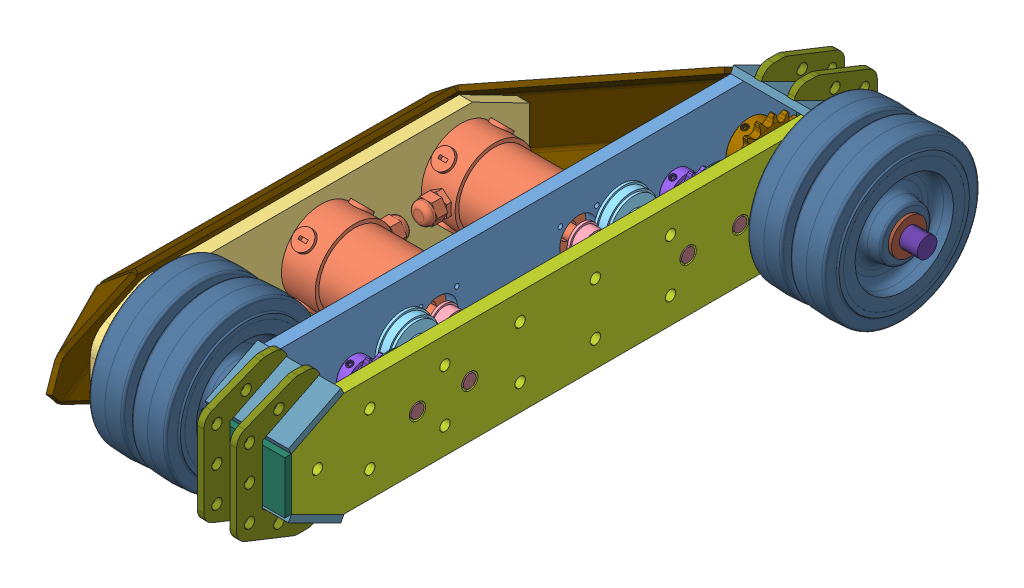
SolidWorks assembly PhobusWheelPod, configuration Default. Lengths in mm.
Overall size (564.9 195.73 652.93).
50 component instances, 18 part files, 92 mates.
Components (placement in the parent):
- WheelPodMotorFaceRail-1: WheelPodMotorFaceRail [Default] at (-65.4677 24.4329 -61.6038) size (12.7 101.6 558.8)
- s28-150magmotor-1: s28-150magmotor [Default] at (-65.4677 24.4329 -61.6038) x (1 0 0) z (0 0.707107 0.707107) size (163.83 88.45 88.45)
- WheelPodOuterRail-1: WheelPodOuterRail [Default] at (-179.7677 24.4329 -61.6038) size (12.7 101.6 414.02)
- Gear16T16P_6325K13-1: Gear16T16P_6325K13 [Default] at (-49.5927 24.4329 -61.6038) x (1 0 0) z (0 -0.155736 0.987799) size (23.81 28.7 28.7)
- Gear32T16P_6325K21 MOD-1: Gear32T16P_6325K21 MOD [Default] at (-49.5927 24.4329 -23.5038) size (25.4 54.1 54.1)
- Gear48T16P_6325K21-2: Gear48T16P_6325K21 [Default] at (-0.3802 24.4329 27.2962) x (-1 0 0) z (0 -0.862539 -0.505991) size (25.4 79.5 79.5)
- Gear16T16P_6325K13-2: Gear16T16P_6325K13 [Default] at (-0.3802 24.4329 -23.5038) x (-1 0 0) z (0 0 -1) size (23.81 28.7 28.7)
- WheelPodChassisRail-1: WheelPodChassisRail [Default] at (2.7948 24.4329 -61.6038) size (12.7 101.6 558.8)
- 2500T42 10t Num40 0500Bore-1: 2500T42 10t Num40 0500Bore [2500T421] at (-29.387 24.4329 27.2962) x (0 0.894943 0.446181) z (-1 0 0) size (44.9 46.71 22.23)
- 2500T473 15t Num40 0750Bore-1: 2500T473 15t Num40 0750Bore [2500T473] at (-29.387 24.4329 99.0512) x (0 0.924225 0.381849) z (-1 0 0) size (67.07 66.71 22.23)
- 6inColsonWithHub-1: 6inColsonWithHub [Default] at (-122.9 18.8142 107.5418) x (1 0 0) z (0 0.938189 0.346124) size (44.45 152.4 152.4)
  - Colson-6in x 1_5in-1: Colson-6in x 1_5in [Default] at (-17.1802 9.9106 2.3327) size (41.28 152.4 152.4)
    - Colson-4.06108.449_Wheel series 4_6Hi-tech-performa-flat-tread-1: Colson-4.06108.449_Wheel series 4_6Hi-tech-performa-flat-tread [Default] at origin size (41.28 152.4 152.4)
  - 1-625in Wide ColsonHubCappedFlanged-1: 1-625in Wide ColsonHubCappedFlanged [Default] at (-37.8177 9.9106 2.3327) size (44.45 34.29 34.29)
- 6inColsonWithHub-2: 6inColsonWithHub [Default] at (-115.9854 23.7371 109.2088) x (-1 0 0) z (0 -0.955464 -0.295107) size (44.45 152.4 152.4)
  - Colson-6in x 1_5in-1: Colson-6in x 1_5in [Default] at (-17.1802 9.9106 2.3327) size (41.28 152.4 152.4)
    - Colson-4.06108.449_Wheel series 4_6Hi-tech-performa-flat-tread-1: Colson-4.06108.449_Wheel series 4_6Hi-tech-performa-flat-tread [Default] at origin size (41.28 152.4 152.4)
  - 1-625in Wide ColsonHubCappedFlanged-1: 1-625in Wide ColsonHubCappedFlanged [Default] at (-37.8177 9.9106 2.3327) size (44.45 34.29 34.29)
- WheelPod 0750 shaft-1: WheelPod 0750 shaft [Default] at (-179.7677 24.4329 99.0512) size (171.45 19.05 19.05)
- WheelPod 0500 shaft-1: WheelPod 0500 shaft [Default] at (-65.4677 24.4329 27.2962) size (80.96 12.7 12.7)
- WheelPod 0500 shaft-2: WheelPod 0500 shaft [Default] at (-65.4677 24.4329 -23.5038) size (80.96 12.7 12.7)
- DrivePodFrontAnglePlate-1: DrivePodFrontAnglePlate [Default] at (-24.9865 62.6121 124.293) x (1 0 0) z (0 -0.447214 0.894427) size (80.96 6.35 57.15)
- DrivePodFrontAnglePlate-2: DrivePodFrontAnglePlate [Default] at (-24.9865 -19.4258 127.1328) x (1 0 0) z (0 0.447214 0.894427) size (80.96 6.35 57.15)
- DrivePodFrontPlate-1: DrivePodFrontPlate [Default] at (-24.9865 24.4329 149.8512) x (1 0 0) z (0 -1 0) size (80.96 6.35 50.8)
- PodAttachmentBracket-1: PodAttachmentBracket [Default] at (-50.3865 24.4329 -61.6038) size (6.35 133.35 81.05)
- PodAttachmentBracket-2: PodAttachmentBracket [Default] at (-18.6365 24.4329 -61.6038) size (6.35 133.35 81.05)
- s28-150magmotor-2: s28-150magmotor [Default] at (-65.4677 24.4329 -197.4938) x (1 0 0) z (0 -0.707107 -0.707107) size (163.83 88.45 88.45)
- Gear16T16P_6325K13-3: Gear16T16P_6325K13 [Default] at (-49.5927 24.4329 -197.4938) x (1 0 0) z (0 -0.155736 0.987799) size (23.81 28.7 28.7)
- Gear32T16P_6325K21 MOD-2: Gear32T16P_6325K21 MOD [Default] at (-49.5927 24.4329 -235.5938) size (25.4 54.1 54.1)
- Gear48T16P_6325K21-3: Gear48T16P_6325K21 [Default] at (-0.3802 24.4329 -286.3938) x (-1 0 0) z (0 -0.862539 -0.505991) size (25.4 79.5 79.5)
- Gear16T16P_6325K13-4: Gear16T16P_6325K13 [Default] at (-0.3802 24.4329 -235.5938) x (-1 0 0) z (0 0 -1) size (23.81 28.7 28.7)
- 2500T42 10t Num40 0500Bore-2: 2500T42 10t Num40 0500Bore [2500T421] at (-29.387 24.4329 -286.3938) x (0 0.894943 0.446181) z (-1 0 0) size (44.9 46.71 22.23)
- 2500T473 15t Num40 0750Bore-2: 2500T473 15t Num40 0750Bore [2500T473] at (-29.387 24.4329 -358.1488) x (0 0.924225 0.381849) z (-1 0 0) size (67.07 66.71 22.23)
- 6inColsonWithHub-3: 6inColsonWithHub [Default] at (59.6625 18.8142 -349.6582) x (1 0 0) z (0 0.938189 0.346124) size (44.45 152.4 152.4)
  - Colson-6in x 1_5in-1: Colson-6in x 1_5in [Default] at (-17.1802 9.9106 2.3327) size (41.28 152.4 152.4)
    - Colson-4.06108.449_Wheel series 4_6Hi-tech-performa-flat-tread-1: Colson-4.06108.449_Wheel series 4_6Hi-tech-performa-flat-tread [Default] at origin size (41.28 152.4 152.4)
  - 1-625in Wide ColsonHubCappedFlanged-1: 1-625in Wide ColsonHubCappedFlanged [Default] at (-37.8177 9.9106 2.3327) size (44.45 34.29 34.29)
- WheelPod 0500 shaft-3: WheelPod 0500 shaft [Default] at (-65.4677 24.4329 -286.3938) size (80.96 12.7 12.7)
- WheelPod 0500 shaft-4: WheelPod 0500 shaft [Default] at (-65.4677 24.4329 -235.5938) size (80.96 12.7 12.7)
- WheelPod 0750 shaft Rear-1: WheelPod 0750 shaft Rear [Default] at (-65.4677 24.4329 -358.1488) size (190.5 19.05 19.05)
- 6inColsonWithHub-4: 6inColsonWithHub [Default] at (66.5771 14.4402 -356.1979) x (-1 0 0) z (0 0.038351 -0.999264) size (44.45 152.4 152.4)
  - Colson-6in x 1_5in-1: Colson-6in x 1_5in [Default] at (-17.1802 9.9106 2.3327) size (41.28 152.4 152.4)
    - Colson-4.06108.449_Wheel series 4_6Hi-tech-performa-flat-tread-1: Colson-4.06108.449_Wheel series 4_6Hi-tech-performa-flat-tread [Default] at origin size (41.28 152.4 152.4)
  - 1-625in Wide ColsonHubCappedFlanged-1: 1-625in Wide ColsonHubCappedFlanged [Default] at (-37.8177 9.9106 2.3327) size (44.45 34.29 34.29)
- DrivePodFrontPlate-2: DrivePodFrontPlate [Default] at (-24.9865 24.4329 -415.2988) x (1 0 0) z (0 -1 0) size (80.96 6.35 50.8)
- DrivePodFrontAnglePlate-3: DrivePodFrontAnglePlate [Default] at (-24.9865 -19.4258 -386.2303) x (1 0 0) z (0 -0.447214 0.894427) size (80.96 6.35 57.15)
- PodAttachmentBracket-3: PodAttachmentBracket [Default] at (-31.3365 24.4329 -197.4938) x (-1 0 0) z (0 0 -1) size (6.35 133.35 81.05)
- DrivePodFrontAnglePlate-4: DrivePodFrontAnglePlate [Default] at (-24.9865 62.6121 -383.3905) x (1 0 0) z (0 0.447214 0.894427) size (80.96 6.35 57.15)
- PodAttachmentBracket-4: PodAttachmentBracket [Default] at (0.4135 24.4329 -197.4938) x (-1 0 0) z (0 0 -1) size (6.35 133.35 81.05)
- DrivePodSideArmorPanelA-1: DrivePodSideArmorPanelA [Default] at (-140.0311 24.4329 -322.1877) x (-0.619644 0 0.784883) z (0 1 0) size (543.24 290.85 112.3)
Mates (geometry in assembly coordinates):
- Concentric1: concentric aligned: cylinder of s28-150magmotor-1 through (-21.5257 24.4329 -61.6038) axis (-1 0 0) radius 6.35; cylinder of WheelPodMotorFaceRail-1 through (-52.7677 24.4329 -61.6038) axis (-1 0 0) radius 18.415
- Coincident1: coincident anti-aligned: plane of WheelPodMotorFaceRail-1 through (-65.4677 24.4329 -61.6038) normal (-1 0 0); plane of s28-150magmotor-1 through (-65.4677 24.4329 -61.6038) normal (1 0 0)
- Parallel1: parallel aligned: plane of WheelPodMotorFaceRail-1 through (-52.7677 75.2329 -61.6038) normal (0 1 0); plane of s28-150magmotor-1 through (-154.0752 34.4329 -114.6038) normal (0 1 0)
- Coincident2: coincident anti-aligned: plane of s28-150magmotor-1 through (-167.0677 24.4329 -61.6038) normal (-1 0 0); plane of WheelPodOuterRail-1 through (-167.0677 24.4329 -61.6038) normal (1 0 0)
- Concentric2: concentric anti-aligned: cylinder of s28-150magmotor-1 through (-185.3557 24.4329 -61.6038) axis (1 0 0) radius 6.35; cylinder of WheelPodOuterRail-1 through (-167.0677 24.4329 -61.6038) axis (-1 0 0) radius 7.9375
- Coincident3: coincident aligned: plane of WheelPodMotorFaceRail-1 through (-52.7677 75.2329 -61.6038) normal (0 1 0); plane of WheelPodOuterRail-1 through (-167.0677 75.2329 -61.6038) normal (0 1 0)
- Distance1: distance = 3.175 mm anti-aligned: plane of Gear32T16P_6325K21 MOD-1 through (-49.5927 24.4329 -23.5038) normal (-1 0 0); plane of WheelPodMotorFaceRail-1 through (-52.7677 24.4329 -61.6038) normal (1 0 0)
- Concentric3: concentric aligned: cylinder of WheelPodMotorFaceRail-1 through (-52.7677 24.4329 -23.5038) axis (-1 0 0) radius 7.9375; cylinder of Gear32T16P_6325K21 MOD-1 through (-24.1927 24.4329 -23.5038) axis (-1 0 0) radius 6.35
- Coincident5: coincident aligned: plane of Gear32T16P_6325K21 MOD-1 through (-36.8927 24.4329 -23.5038) normal (1 0 0); plane of Gear16T16P_6325K13-1 through (-36.8927 24.4329 -61.6038) normal (1 0 0)
- Concentric4: concentric aligned: cylinder of s28-150magmotor-1 through (-21.5257 24.4329 -61.6038) axis (-1 0 0) radius 6.35; cylinder of Gear16T16P_6325K13-1 through (-25.7802 24.4329 -61.6038) axis (-1 0 0) radius 6.35
- Coincident9: coincident aligned: plane of WheelPodMotorFaceRail-1 through (-52.7677 75.2329 -61.6038) normal (0 1 0); plane of WheelPodChassisRail-1 through (15.4948 75.2329 -61.6038) normal (0 1 0)
- Concentric10: concentric aligned: cylinder of WheelPodOuterRail-1 through (-167.0677 24.4329 99.0512) axis (-1 0 0) radius 11.1125; cylinder of 6inColsonWithHub-1/1-625in Wide ColsonHubCappedFlanged-1 through (-119.4427 24.4329 99.0512) axis (-1 0 0) radius 6.35
- Concentric12: concentric anti-aligned: cylinder of WheelPodOuterRail-1 through (-167.0677 24.4329 99.0512) axis (-1 0 0) radius 11.1125; cylinder of 6inColsonWithHub-2/1-625in Wide ColsonHubCappedFlanged-1 through (-119.4427 24.4329 99.0512) axis (1 0 0) radius 6.35
- Concentric13: concentric aligned: cylinder of WheelPodMotorFaceRail-1 through (-52.7677 24.4329 99.0512) axis (-1 0 0) radius 11.1125; cylinder of WheelPodOuterRail-1 through (-167.0677 24.4329 99.0512) axis (-1 0 0) radius 11.1125
- Coincident13: coincident anti-aligned: plane of 6inColsonWithHub-1/1-625in Wide ColsonHubCappedFlanged-1 through (-119.4427 24.4329 99.0512) normal (1 0 0); plane of 6inColsonWithHub-2/1-625in Wide ColsonHubCappedFlanged-1 through (-119.4427 24.4329 99.0512) normal (-1 0 0)
- Distance4: distance = 3.175 mm anti-aligned: plane of 6inColsonWithHub-1/1-625in Wide ColsonHubCappedFlanged-1 through (-163.8927 24.4329 99.0512) normal (-1 0 0); plane of WheelPodOuterRail-1 through (-167.0677 24.4329 -61.6038) normal (1 0 0)
- Concentric14: concentric anti-aligned: cylinder of Gear32T16P_6325K21 MOD-1 through (-24.1927 24.4329 -23.5038) axis (-1 0 0) radius 6.35; cylinder of Gear16T16P_6325K13-2 through (-24.1927 24.4329 -23.5038) axis (1 0 0) radius 6.35
- Coincident14: coincident aligned: plane of Gear32T16P_6325K21 MOD-1 through (-24.1927 24.4329 -25.0913) normal (0 0 1); plane of Gear16T16P_6325K13-2 through (-24.1927 24.4329 -25.0913) normal (0 0 1)
- Coincident15: coincident anti-aligned: plane of Gear32T16P_6325K21 MOD-1 through (-24.1927 24.4329 -23.5038) normal (1 0 0); plane of Gear16T16P_6325K13-2 through (-24.1927 24.4329 -23.5038) normal (-1 0 0)
- Coincident16: coincident aligned: plane of Gear48T16P_6325K21-2 through (-0.3802 24.4329 27.2962) normal (1 0 0); plane of Gear16T16P_6325K13-2 through (-0.3802 24.4329 -23.5038) normal (1 0 0)
- Concentric15: concentric aligned: cylinder of Gear48T16P_6325K21-2 through (-25.7802 24.4329 27.2962) axis (1 0 0) radius 6.35; cylinder of 2500T42 10t Num40 0500Bore-1 through (-48.0052 24.4329 27.2962) axis (1 0 0) radius 6.35
- Concentric16: concentric anti-aligned: cylinder of WheelPodMotorFaceRail-1 through (-52.7677 24.4329 27.2962) axis (-1 0 0) radius 7.9375; cylinder of Gear48T16P_6325K21-2 through (-25.7802 24.4329 27.2962) axis (1 0 0) radius 6.35
- Coincident17: coincident anti-aligned: plane of Gear48T16P_6325K21-2 through (-25.7802 24.4329 27.2962) normal (-1 0 0); plane of 2500T42 10t Num40 0500Bore-1 through (-25.7802 16.8464 42.5132) normal (1 0 0)
- Concentric17: concentric anti-aligned: cylinder of WheelPodMotorFaceRail-1 through (-52.7677 24.4329 99.0512) axis (-1 0 0) radius 11.1125; cylinder of 2500T473 15t Num40 0750Bore-1 through (-48.0052 24.4329 99.0512) axis (1 0 0) radius 9.525
- Coincident18: coincident aligned: plane of 2500T42 10t Num40 0500Bore-1 through (-25.7802 16.8464 42.5132) normal (1 0 0); plane of 2500T473 15t Num40 0750Bore-1 through (-25.7802 13.9953 124.3144) normal (1 0 0)
- Distance5: distance = 3.175 mm anti-aligned: plane of WheelPodChassisRail-1 through (2.7948 24.4329 -61.6038) normal (-1 0 0); plane of Gear48T16P_6325K21-2 through (-0.3802 24.4329 27.2962) normal (1 0 0)
- Coincident19: coincident aligned: plane of WheelPodOuterRail-1 through (-179.7677 24.4329 -61.6038) normal (-1 0 0); plane of WheelPod 0750 shaft-1 through (-179.7677 24.4329 99.0512) normal (-1 0 0)
- Concentric18: concentric aligned: cylinder of WheelPodOuterRail-1 through (-167.0677 24.4329 99.0512) axis (-1 0 0) radius 11.1125; cylinder of WheelPod 0750 shaft-1 through (-8.3177 24.4329 99.0512) axis (-1 0 0) radius 9.525
- Concentric19: concentric aligned: cylinder of WheelPodChassisRail-1 through (15.4948 24.4329 -23.5038) axis (-1 0 0) radius 7.9375; cylinder of WheelPod 0500 shaft-2 through (15.4948 24.4329 -23.5038) axis (-1 0 0) radius 6.35
- Concentric20: concentric aligned: cylinder of WheelPodChassisRail-1 through (15.4948 24.4329 27.2962) axis (-1 0 0) radius 7.9375; cylinder of WheelPod 0500 shaft-1 through (15.4948 24.4329 27.2962) axis (-1 0 0) radius 6.35
- Coincident20: coincident aligned: plane of WheelPodChassisRail-1 through (15.4948 24.4329 -61.6038) normal (1 0 0); plane of WheelPod 0500 shaft-2 through (15.4948 24.4329 -23.5038) normal (1 0 0)
- Coincident21: coincident aligned: plane of WheelPodChassisRail-1 through (15.4948 24.4329 -61.6038) normal (1 0 0); plane of WheelPod 0500 shaft-1 through (15.4948 24.4329 27.2962) normal (1 0 0)
- Coincident22: coincident aligned: plane of WheelPodMotorFaceRail-1 through (-65.4677 24.4329 149.8512) normal (0 0 1); plane of WheelPodChassisRail-1 through (2.7948 49.8329 149.8512) normal (0 0 1)
- Coincident23: coincident aligned: plane of WheelPodMotorFaceRail-1 through (-52.7677 75.2329 -61.6038) normal (0 1 0); plane of WheelPodChassisRail-1 through (15.4948 75.2329 -61.6038) normal (0 1 0)
- Coincident30: coincident anti-aligned: plane of WheelPodChassisRail-1 through (2.7948 -0.9671 149.8512) normal (0 -0.894427 0.447214); plane of DrivePodFrontAnglePlate-2 through (-24.9865 -13.7462 124.293) normal (0 0.894427 -0.447214)
- Coincident31: coincident aligned: line of WheelPodChassisRail-1 through (2.7948 -0.9671 149.8512) axis (1 0 0); line of DrivePodFrontAnglePlate-2 through (-65.4677 -0.9671 149.8512) axis (1 0 0)
- Coincident32: coincident anti-aligned: plane of WheelPodChassisRail-1 through (2.7948 49.8329 149.8512) normal (0 0.894427 0.447214); plane of DrivePodFrontAnglePlate-1 through (-24.9865 62.6121 124.293) normal (0 -0.894427 -0.447214)
- Coincident33: coincident aligned: line of WheelPodChassisRail-1 through (2.7948 49.8329 149.8512) axis (1 0 0); line of DrivePodFrontAnglePlate-1 through (-65.4677 49.8329 149.8512) axis (1 0 0)
- Coincident34: coincident aligned: plane of WheelPodChassisRail-1 through (15.4948 24.4329 -61.6038) normal (1 0 0); plane of DrivePodFrontAnglePlate-1 through (15.4948 55.5126 152.691) normal (1 0 0)
- Coincident35: coincident aligned: plane of WheelPodChassisRail-1 through (15.4948 24.4329 -61.6038) normal (1 0 0); plane of DrivePodFrontAnglePlate-2 through (15.4948 -0.9671 149.8512) normal (1 0 0)
- Coincident36: coincident anti-aligned: plane of WheelPodChassisRail-1 through (2.7948 49.8329 149.8512) normal (0 0 1); plane of DrivePodFrontPlate-1 through (-24.9865 24.4329 149.8512) normal (0 0 -1)
- Coincident37: coincident aligned: plane of WheelPodChassisRail-1 through (15.4948 24.4329 -61.6038) normal (1 0 0); plane of DrivePodFrontPlate-1 through (15.4948 -0.9671 156.2012) normal (1 0 0)
- Coincident38: coincident aligned: line of DrivePodFrontAnglePlate-2 through (-65.4677 -0.9671 149.8512) axis (1 0 0); line of DrivePodFrontPlate-1 through (-65.4677 -0.9671 149.8512) axis (1 0 0)
- Coincident48: coincident aligned: plane of PodAttachmentBracket-1 through (-44.0365 145.7557 -13.5189) normal (0 0.929646 0.368454); plane of PodAttachmentBracket-2 through (-12.2865 145.7557 -13.5189) normal (0 0.929646 0.368454)
- Coincident50: coincident anti-aligned: plane of DrivePodFrontAnglePlate-1 through (-24.9865 68.2917 127.1328) normal (0 0.894427 0.447214); plane of PodAttachmentBracket-2 through (-12.2865 135.0146 -6.313) normal (0 -0.894427 -0.447214)
- Coincident51: coincident anti-aligned: plane of DrivePodFrontPlate-1 through (-24.9865 24.4329 156.2012) normal (0 0 1); plane of PodAttachmentBracket-1 through (-44.0365 24.4329 156.2012) normal (0 0 -1)
- Distance6: distance = 21.4312 mm aligned: plane of PodAttachmentBracket-2 through (-5.9365 24.4329 -61.6038) normal (1 0 0); plane of DrivePodFrontAnglePlate-1 through (15.4948 55.5126 152.691) normal (1 0 0)
- Distance7: distance = 21.4312 mm aligned: plane of DrivePodFrontAnglePlate-1 through (-65.4677 55.5126 152.691) normal (-1 0 0); plane of PodAttachmentBracket-1 through (-44.0365 24.4329 -61.6038) normal (-1 0 0)
- Coincident54: coincident aligned: plane of PodAttachmentBracket-1 through (-44.0365 -28.9987 45.2595) normal (0 0.447214 -0.894427); plane of PodAttachmentBracket-2 through (-12.2865 -28.9987 45.2595) normal (0 0.447214 -0.894427)
- Coincident55: coincident anti-aligned: plane of WheelPodMotorFaceRail-1 through (-65.4677 24.4329 -61.6038) normal (-1 0 0); plane of s28-150magmotor-2 through (-65.4677 24.4329 -197.4938) normal (1 0 0)
- Concentric21: concentric anti-aligned: cylinder of WheelPodMotorFaceRail-1 through (-65.4677 42.1241 -179.8027) axis (-1 0 0) radius 2.2479; cylinder of s28-150magmotor-2 through (-78.1677 42.1241 -179.8027) axis (1 0 0) radius 2.25
- Concentric22: concentric aligned: cylinder of WheelPodMotorFaceRail-1 through (-52.7677 24.4329 -197.4938) axis (-1 0 0) radius 18.415; cylinder of s28-150magmotor-2 through (-21.5257 24.4329 -197.4938) axis (-1 0 0) radius 6.35
- Coincident56: coincident aligned: plane of WheelPodChassisRail-1 through (15.4948 24.4329 -61.6038) normal (1 0 0); circle of WheelPod 0500 shaft-4
- Concentric23: concentric aligned: cylinder of WheelPodChassisRail-1 through (15.4948 24.4329 -235.5938) axis (-1 0 0) radius 7.9375; cylinder of WheelPod 0500 shaft-4 through (15.4948 24.4329 -235.5938) axis (-1 0 0) radius 6.35
- Concentric24: concentric aligned: cylinder of WheelPodChassisRail-1 through (15.4948 24.4329 -286.3938) axis (-1 0 0) radius 7.9375; cylinder of WheelPod 0500 shaft-3 through (15.4948 24.4329 -286.3938) axis (-1 0 0) radius 6.35
- Coincident57: coincident aligned: plane of WheelPodChassisRail-1 through (15.4948 24.4329 -61.6038) normal (1 0 0); plane of WheelPod 0500 shaft-3 through (15.4948 24.4329 -286.3938) normal (1 0 0)
- Coincident58: coincident aligned: plane of Gear16T16P_6325K13-1 through (-25.7802 24.4329 -61.6038) normal (1 0 0); plane of Gear16T16P_6325K13-3 through (-25.7802 24.4329 -197.4938) normal (1 0 0)
- Concentric25: concentric aligned: cylinder of s28-150magmotor-2 through (-21.5257 24.4329 -197.4938) axis (-1 0 0) radius 6.35; cylinder of Gear16T16P_6325K13-3 through (-25.7802 24.4329 -197.4938) axis (-1 0 0) radius 6.35
- Coincident59: coincident aligned: plane of Gear32T16P_6325K21 MOD-1 through (-36.8927 24.4329 -23.5038) normal (1 0 0); plane of Gear32T16P_6325K21 MOD-2 through (-36.8927 24.4329 -235.5938) normal (1 0 0)
- Concentric26: concentric aligned: cylinder of Gear32T16P_6325K21 MOD-2 through (-24.1927 24.4329 -235.5938) axis (-1 0 0) radius 6.35; cylinder of WheelPod 0500 shaft-4 through (15.4948 24.4329 -235.5938) axis (-1 0 0) radius 6.35
- Coincident60: coincident aligned: plane of Gear16T16P_6325K13-2 through (-2.9202 24.4329 -23.5038) normal (-1 0 0); plane of Gear16T16P_6325K13-4 through (-2.9202 24.4329 -235.5938) normal (-1 0 0)
- Concentric27: concentric anti-aligned: cylinder of Gear16T16P_6325K13-4 through (-24.1927 24.4329 -235.5938) axis (1 0 0) radius 6.35; cylinder of WheelPod 0500 shaft-4 through (15.4948 24.4329 -235.5938) axis (-1 0 0) radius 6.35
- Coincident61: coincident aligned: plane of Gear48T16P_6325K21-2 through (-13.0802 24.4329 27.2962) normal (-1 0 0); plane of Gear48T16P_6325K21-3 through (-13.0802 24.4329 -286.3938) normal (-1 0 0)
- Concentric28: concentric anti-aligned: cylinder of Gear48T16P_6325K21-3 through (-25.7802 24.4329 -286.3938) axis (1 0 0) radius 6.35; cylinder of WheelPod 0500 shaft-3 through (15.4948 24.4329 -286.3938) axis (-1 0 0) radius 6.35
- Coincident62: coincident aligned: plane of 2500T42 10t Num40 0500Bore-1 through (-25.7802 16.8464 42.5132) normal (1 0 0); plane of 2500T42 10t Num40 0500Bore-2 through (-25.7802 16.8464 -271.1768) normal (1 0 0)
- Concentric29: concentric anti-aligned: cylinder of 2500T42 10t Num40 0500Bore-2 through (-48.0052 24.4329 -286.3938) axis (1 0 0) radius 6.35; cylinder of WheelPod 0500 shaft-3 through (15.4948 24.4329 -286.3938) axis (-1 0 0) radius 6.35
- Coincident63: coincident aligned: plane of 2500T473 15t Num40 0750Bore-1 through (-25.7802 13.9953 124.3144) normal (1 0 0); plane of 2500T473 15t Num40 0750Bore-2 through (-25.7802 13.9953 -332.8856) normal (1 0 0)
- Concentric30: concentric anti-aligned: cylinder of WheelPodMotorFaceRail-1 through (-52.7677 24.4329 -358.1488) axis (-1 0 0) radius 11.1125; cylinder of 2500T473 15t Num40 0750Bore-2 through (-48.0052 24.4329 -358.1488) axis (1 0 0) radius 9.525
- Coincident64: coincident aligned: plane of WheelPodMotorFaceRail-1 through (-65.4677 24.4329 -61.6038) normal (-1 0 0); plane of WheelPod 0750 shaft Rear-1 through (-65.4677 24.4329 -358.1488) normal (-1 0 0)
- Concentric31: concentric aligned: cylinder of WheelPodMotorFaceRail-1 through (-52.7677 24.4329 -358.1488) axis (-1 0 0) radius 11.1125; cylinder of WheelPod 0750 shaft Rear-1 through (125.0323 24.4329 -358.1488) axis (-1 0 0) radius 9.525
- Distance8: distance = 3.175 mm anti-aligned: plane of 6inColsonWithHub-3/1-625in Wide ColsonHubCappedFlanged-1 through (18.6698 24.4329 -358.1488) normal (-1 0 0); plane of WheelPodChassisRail-1 through (15.4948 24.4329 -61.6038) normal (1 0 0)
- Concentric32: concentric aligned: cylinder of 6inColsonWithHub-3/1-625in Wide ColsonHubCappedFlanged-1 through (63.1198 24.4329 -358.1488) axis (-1 0 0) radius 6.35; cylinder of WheelPod 0750 shaft Rear-1 through (125.0323 24.4329 -358.1488) axis (-1 0 0) radius 9.525
- Concentric33: concentric anti-aligned: cylinder of WheelPod 0750 shaft Rear-1 through (125.0323 24.4329 -358.1488) axis (-1 0 0) radius 9.525; cylinder of 6inColsonWithHub-4/1-625in Wide ColsonHubCappedFlanged-1 through (63.1198 24.4329 -358.1488) axis (1 0 0) radius 6.35
- Coincident65: coincident anti-aligned: plane of 6inColsonWithHub-3/1-625in Wide ColsonHubCappedFlanged-1 through (63.1198 24.4329 -358.1488) normal (1 0 0); plane of 6inColsonWithHub-4/1-625in Wide ColsonHubCappedFlanged-1 through (63.1198 24.4329 -358.1488) normal (-1 0 0)
- Coincident66: coincident anti-aligned: plane of WheelPodMotorFaceRail-1 through (-65.4677 49.8329 -408.9488) normal (0 0 -1); plane of DrivePodFrontPlate-2 through (-24.9865 24.4329 -408.9488) normal (0 0 1)
- Coincident67: coincident: line of WheelPodMotorFaceRail-1 through (-65.4677 49.8329 -408.9488) axis (1 0 0); plane of DrivePodFrontPlate-2 through (-65.4677 49.8329 -408.9488) normal (0 1 0)
- Coincident68: coincident aligned: plane of WheelPodMotorFaceRail-1 through (-65.4677 24.4329 -61.6038) normal (-1 0 0); plane of DrivePodFrontPlate-2 through (-65.4677 -0.9671 -408.9488) normal (-1 0 0)
- Coincident69: coincident anti-aligned: plane of WheelPodMotorFaceRail-1 through (-65.4677 -0.9671 -408.9488) normal (0 -0.894427 -0.447214); plane of DrivePodFrontAnglePlate-3 through (-24.9865 -13.7462 -383.3905) normal (0 0.894427 0.447214)
- Coincident70: coincident anti-aligned: plane of WheelPodMotorFaceRail-1 through (-65.4677 75.2329 -358.1488) normal (0 0.894427 -0.447214); plane of DrivePodFrontAnglePlate-4 through (-24.9865 62.6121 -383.3905) normal (0 -0.894427 0.447214)
- Coincident71: coincident anti-aligned: line of DrivePodFrontPlate-2 through (-65.4677 -0.9671 -408.9488) axis (1 0 0); line of DrivePodFrontAnglePlate-3 through (15.4948 -0.9671 -408.9488) axis (-1 0 0)
- Coincident72: coincident aligned: line of DrivePodFrontPlate-2 through (15.4948 49.8329 -408.9488) axis (-1 0 0); line of DrivePodFrontAnglePlate-4 through (15.4948 49.8329 -408.9488) axis (-1 0 0)
- Coincident73: coincident aligned: plane of WheelPodMotorFaceRail-1 through (-65.4677 24.4329 -61.6038) normal (-1 0 0); plane of DrivePodFrontAnglePlate-4 through (-65.4677 81.0708 -360.6721) normal (-1 0 0)
- Coincident74: coincident aligned: plane of WheelPodMotorFaceRail-1 through (-65.4677 24.4329 -61.6038) normal (-1 0 0); plane of DrivePodFrontAnglePlate-3 through (-65.4677 -26.5253 -357.8322) normal (-1 0 0)
- Coincident75: coincident aligned: plane of PodAttachmentBracket-3 through (-37.6865 24.4329 -415.2988) normal (0 0 1); plane of PodAttachmentBracket-4 through (-5.9365 24.4329 -415.2988) normal (0 0 1)
- Coincident76: coincident aligned: plane of PodAttachmentBracket-3 through (-37.6865 -86.1487 -252.7846) normal (0 0.894427 0.447214); plane of PodAttachmentBracket-4 through (-5.9365 -86.1487 -252.7846) normal (0 0.894427 0.447214)
- Coincident77: coincident anti-aligned: plane of DrivePodFrontPlate-2 through (-24.9865 24.4329 -415.2988) normal (0 0 -1); plane of PodAttachmentBracket-4 through (-5.9365 24.4329 -415.2988) normal (0 0 1)
- Coincident78: coincident anti-aligned: plane of DrivePodFrontAnglePlate-3 through (-24.9865 -19.4258 -386.2303) normal (0 -0.894427 -0.447214); plane of PodAttachmentBracket-4 through (-5.9365 -86.1487 -252.7846) normal (0 0.894427 0.447214)
- Coincident79: coincident aligned: plane of PodAttachmentBracket-1 through (-44.0365 24.4329 -61.6038) normal (-1 0 0); plane of PodAttachmentBracket-3 through (-44.0365 24.4329 -197.4938) normal (-1 0 0)
- Coincident80: coincident aligned: plane of PodAttachmentBracket-2 through (-12.2865 24.4329 -61.6038) normal (-1 0 0); plane of PodAttachmentBracket-4 through (-12.2865 24.4329 -197.4938) normal (-1 0 0)
- Coincident84: coincident aligned: line of WheelPodMotorFaceRail-1 through (-65.4677 49.8329 -408.9488) axis (0 -1 0); line of DrivePodSideArmorPanelA-1 through (-65.4677 46.7159 -408.9488) axis (0 -1 0)
- Coincident87: coincident: line of WheelPodOuterRail-1 through (-179.7677 46.7159 -264.1688) axis (0 -1 0); plane of DrivePodSideArmorPanelA-1 through (-136.2931 24.4329 -319.2367) normal (0.784883 0 0.619644)
- Coincident88: coincident: moEndPointRef_w of DrivePodSideArmorPanelA-1; moEndPointRef_w of DrivePodFrontPlate-2
